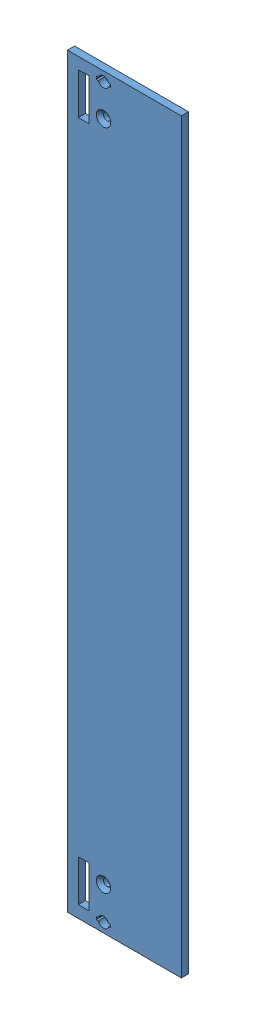
SolidWorks assembly VME-6U-front-panel, configuration Default. Lengths in mm.
Overall size (40 262 165.5).
2 component instances, 2 part files, 3 mates.
Components (placement in the parent):
- VME-6U-front-panel-1: VME-6U-front-panel [Default] at origin size (40 262 2.5)
- VME-6U-PCB.FTSW-1: VME-6U-PCB.FTSW [Default] at (2.25 14 -3) size (27.59 233 165)
Mates (geometry in assembly coordinates):
- Coincident1: coincident anti-aligned: plane of VME-6U-PCB.FTSW-1 through (2.25 14 -3) normal (-1 0 0); plane of assembly through (2.25 0 0) normal (1 0 0)
- Distance1: distance = 14 mm aligned: plane of VME-6U-front-panel-1 through (0 0 2.5) normal (0 -1 0); plane of VME-6U-PCB.FTSW-1 through (3.8375 14 -3) normal (0 -1 0)
- Distance2: distance = 3 mm aligned: plane of VME-6U-front-panel-1 through (0 0 0) normal (0 0 1); plane of VME-6U-PCB.FTSW-1 through (2.25 14 -3) normal (0 0 1)
